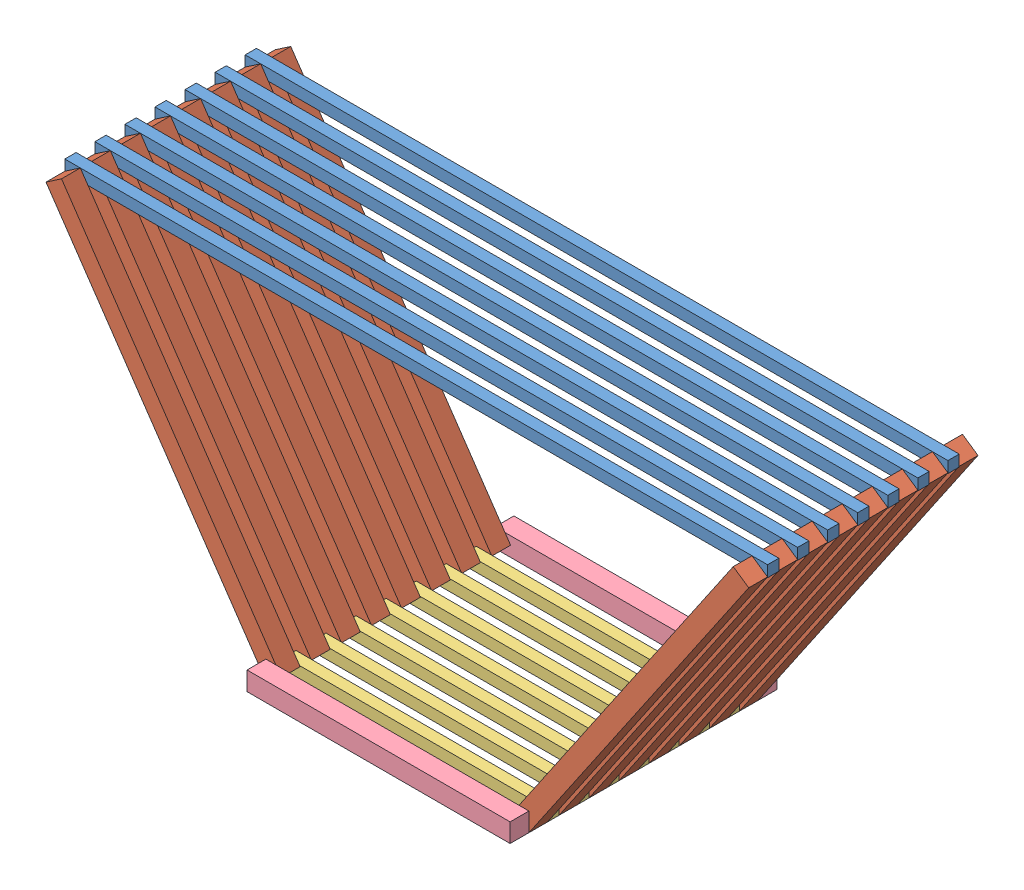
SolidWorks assembly section, configuration Default. Lengths in mm.
Overall size (187 88.5 71).
32 component instances, 4 part files, 107 mates.
Components (placement in the parent):
- bottom-1: bottom [Default] at (-2.2105 97.3296 181.7134) size (187 3 3)
- side-1: side [Default] at (-2.2105 97.5103 186.7134) x (0.563855 -0.825874 0) z (0 0 1) size (103.75 5 5)
- side-2: side [Default] at (126.2895 11.8259 186.7134) x (0.563855 0.825874 0) z (0 0 1) size (103.75 5 5)
- topmid-1: topmid [Default] at (56.2895 11.8259 189.7134) size (70 3 3)
- topmid-3: topmid [Default] at (56.2895 11.8259 181.7134) size (70 3 3)
- bottom-2: bottom [Default] at (-2.2105 97.3296 189.7134) size (187 3 3)
- side-3: side [Default] at (-2.2105 97.5103 138.7134) x (0.563855 -0.825874 0) z (0 0 1) size (103.75 5 5)
- side-4: side [Default] at (126.2895 11.8259 162.7134) x (0.563855 0.825874 0) z (0 0 1) size (103.75 5 5)
- side-5: side [Default] at (126.2895 11.8259 178.7134) x (0.563855 0.825874 0) z (0 0 1) size (103.75 5 5)
- side-6: side [Default] at (-2.2105 97.5103 178.7134) x (0.563855 -0.825874 0) z (0 0 1) size (103.75 5 5)
- side-7: side [Default] at (-2.2105 97.5103 194.7134) x (0.563855 -0.825874 0) z (0 0 1) size (103.75 5 5)
- side-8: side [Default] at (126.2895 11.8259 194.7134) x (0.563855 0.825874 0) z (0 0 1) size (103.75 5 5)
- side-9: side [Default] at (126.2895 11.8259 146.7134) x (0.563855 0.825874 0) z (0 0 1) size (103.75 5 5)
- side-10: side [Default] at (126.2895 11.8259 154.7134) x (0.563855 0.825874 0) z (0 0 1) size (103.75 5 5)
- side-11: side [Default] at (126.2895 11.8259 170.7134) x (0.563855 0.825874 0) z (0 0 1) size (103.75 5 5)
- side-12: side [Default] at (-2.2105 97.5103 162.7134) x (0.563855 -0.825874 0) z (0 0 1) size (103.75 5 5)
- side-13: side [Default] at (-2.2105 97.5103 170.7134) x (0.563855 -0.825874 0) z (0 0 1) size (103.75 5 5)
- side-14: side [Default] at (-2.2105 97.5103 154.7134) x (0.563855 -0.825874 0) z (0 0 1) size (103.75 5 5)
- side-15: side [Default] at (126.2895 11.8259 138.7134) x (0.563855 0.825874 0) z (0 0 1) size (103.75 5 5)
- side-16: side [Default] at (-2.2105 97.5103 146.7134) x (0.563855 -0.825874 0) z (0 0 1) size (103.75 5 5)
- topend-1: topend [Default] at (56.2895 11.8259 199.7134) size (70 5 5)
- topend-2: topend [Default] at (56.2895 11.8259 133.7134) size (70 5 5)
- topmid-4: topmid [Default] at (56.2895 11.8259 157.7134) size (70 3 3)
- topmid-5: topmid [Default] at (56.2895 11.8259 149.7134) size (70 3 3)
- topmid-6: topmid [Default] at (56.2895 11.8259 165.7134) size (70 3 3)
- topmid-7: topmid [Default] at (56.2895 11.8259 173.7134) size (70 3 3)
- topmid-8: topmid [Default] at (56.2895 11.8259 141.7134) size (70 3 3)
- bottom-3: bottom [Default] at (-2.2105 97.3296 173.7134) size (187 3 3)
- bottom-4: bottom [Default] at (-2.2105 97.3296 165.7134) size (187 3 3)
- bottom-5: bottom [Default] at (-2.2105 97.3296 157.7134) size (187 3 3)
- bottom-6: bottom [Default] at (-2.2105 97.3296 149.7134) size (187 3 3)
- bottom-7: bottom [Default] at (-2.2105 97.3296 141.7134) size (187 3 3)
Mates (geometry in assembly coordinates):
- Parallel34: parallel: line of side-7 through (-2.2105 97.5103 194.7134) axis (0.563855 -0.825874 0); line of side-1 through (-2.2105 97.5103 186.7134) axis (0.563855 -0.825874 0)
- Parallel35: parallel: line of topend-1 through (56.2895 11.8259 199.7134) axis (1 0 0); line of topmid-3 through (56.2895 11.8259 181.7134) axis (1 0 0)
- Parallel36: parallel: line of topend-1 through (56.2895 11.8259 199.7134) axis (1 0 0); line of topmid-7 through (56.2895 11.8259 173.7134) axis (1 0 0)
- Parallel37: parallel: line of topend-1 through (56.2895 11.8259 199.7134) axis (1 0 0); line of bottom-2 through (-2.2105 97.3296 189.7134) axis (1 0 0)
- Parallel38: parallel: line of topend-1 through (56.2895 11.8259 199.7134) axis (1 0 0); line of bottom-1 through (-2.2105 97.3296 181.7134) axis (1 0 0)
- Parallel40: parallel: line of side-1 through (-2.2105 97.5103 186.7134) axis (0.563855 -0.825874 0); line of side-6 through (-2.2105 97.5103 178.7134) axis (0.563855 -0.825874 0)
- Parallel41: parallel: line of side-2 through (126.2895 11.8259 186.7134) axis (0.563855 0.825874 0); line of side-8 through (126.2895 11.8259 194.7134) axis (0.563855 0.825874 0)
- Parallel42: parallel: line of side-2 through (126.2895 11.8259 186.7134) axis (0.563855 0.825874 0); line of side-5 through (126.2895 11.8259 178.7134) axis (0.563855 0.825874 0)
- Parallel43: parallel: line of topend-1 through (56.2895 11.8259 194.7134) axis (0 0 1); line of side-7 through (56.2895 11.8259 194.7134) axis (0 0 -1)
- Parallel44: parallel: line of topend-1 through (56.2895 11.8259 194.7134) axis (0 0 1); line of topmid-1 through (56.2895 11.8259 186.7134) axis (0 0 1)
- Parallel45: parallel: line of topend-1 through (56.2895 11.8259 194.7134) axis (0 0 1); line of side-1 through (56.2895 11.8259 186.7134) axis (0 0 -1)
- Parallel46: parallel: line of topend-1 through (56.2895 11.8259 194.7134) axis (0 0 1); line of topmid-3 through (56.2895 11.8259 178.7134) axis (0 0 1)
- Parallel47: parallel: line of topend-1 through (56.2895 11.8259 194.7134) axis (0 0 1); line of side-6 through (56.2895 11.8259 178.7134) axis (0 0 -1)
- Parallel48: parallel: line of topend-1 through (56.2895 11.8259 194.7134) axis (0 0 1); line of topmid-7 through (56.2895 11.8259 170.7134) axis (0 0 1)
- Parallel49: parallel: line of topend-1 through (56.2895 11.8259 194.7134) axis (0 0 1); line of topmid-7 through (126.2895 11.8259 173.7134) axis (0 0 -1)
- Parallel50: parallel: line of topend-1 through (56.2895 11.8259 194.7134) axis (0 0 1); line of side-5 through (126.2895 11.8259 173.7134) axis (0 0 1)
- Parallel51: parallel: line of topend-1 through (56.2895 11.8259 194.7134) axis (0 0 1); line of topmid-3 through (126.2895 11.8259 181.7134) axis (0 0 -1)
- Parallel52: parallel: line of topend-1 through (56.2895 11.8259 194.7134) axis (0 0 1); line of side-2 through (126.2895 11.8259 181.7134) axis (0 0 1)
- Parallel53: parallel: line of topend-1 through (56.2895 11.8259 194.7134) axis (0 0 1); line of topmid-1 through (126.2895 11.8259 189.7134) axis (0 0 -1)
- Parallel54: parallel: line of topend-1 through (56.2895 11.8259 194.7134) axis (0 0 1); line of side-8 through (126.2895 11.8259 189.7134) axis (0 0 1)
- Parallel55: parallel: line of topend-1 through (56.2895 11.8259 194.7134) axis (0 0 1); line of bottom-1 through (184.7895 97.3296 181.7134) axis (0 0 -1)
- Parallel56: parallel: line of topend-1 through (56.2895 11.8259 194.7134) axis (0 0 1); line of bottom-2 through (184.7895 97.3296 189.7134) axis (0 0 -1)
- Parallel57: parallel: line of topend-1 through (56.2895 11.8259 194.7134) axis (0 0 1); line of side-8 through (184.7895 97.5103 194.7134) axis (0 0 -1)
- Parallel58: parallel: line of topend-1 through (56.2895 11.8259 194.7134) axis (0 0 1); line of side-2 through (184.7895 97.5103 186.7134) axis (0 0 -1)
- Parallel59: parallel: line of topend-1 through (56.2895 11.8259 194.7134) axis (0 0 1); line of side-5 through (184.7895 97.5103 178.7134) axis (0 0 -1)
- Parallel60: parallel: line of topend-1 through (56.2895 11.8259 194.7134) axis (0 0 1); line of side-7 through (-2.2105 97.5103 189.7134) axis (0 0 1)
- Parallel61: parallel: line of topend-1 through (56.2895 11.8259 194.7134) axis (0 0 1); line of bottom-2 through (-2.2105 97.3296 186.7134) axis (0 0 1)
- Parallel62: parallel: line of topend-1 through (56.2895 11.8259 194.7134) axis (0 0 1); line of side-1 through (-2.2105 97.5103 181.7134) axis (0 0 1)
- Parallel63: parallel: line of topend-1 through (56.2895 11.8259 194.7134) axis (0 0 1); line of bottom-1 through (-2.2105 97.3296 178.7134) axis (0 0 1)
- Parallel64: parallel: line of topend-1 through (56.2895 11.8259 194.7134) axis (0 0 1); line of side-6 through (-2.2105 97.5103 173.7134) axis (0 0 1)
- Coincident68: coincident: point of side-7; point of topend-1
- Coincident69: coincident: point of topmid-1; point of side-7
- Coincident70: coincident: point of side-1; point of topmid-1
- Coincident71: coincident: point of side-1; point of topmid-3
- Coincident72: coincident: point of topmid-7; point of side-6
- Coincident73: coincident: point of topmid-3; point of side-6
- Coincident74: coincident: point of side-5; point of topmid-7
- Coincident75: coincident: point of side-2; point of topmid-3
- Coincident76: coincident: point of topmid-1; point of side-8
- Parallel65: parallel: line of topmid-1 through (56.2895 11.8259 189.7134) axis (1 0 0); line of topend-1 through (126.2895 11.8259 194.7134) axis (-1 0 0)
- Coincident85: coincident: point of side-1; line of bottom-2 through (184.7895 100.3296 186.7134) axis (-1 0 0)
- Coincident86: coincident: line of bottom-2 through (-2.2105 100.3296 189.7134) axis (1 0 0); point of side-8
- Coincident88: coincident: line of bottom-2 through (184.7895 100.3296 189.7134) axis (0 -1 0); point of side-8
- Coincident89: coincident: line of bottom-2 through (-2.2105 100.3296 189.7134) axis (0 -1 0); point of side-7
- Coincident90: coincident: line of bottom-1 through (-2.2105 100.3296 181.7134) axis (1 0 0); point of side-2
- Coincident91: coincident: line of bottom-1 through (184.7895 100.3296 181.7134) axis (0 -1 0); point of side-2
- Parallel67: parallel: line of bottom-1 through (184.7895 97.3296 178.7134) axis (-1 0 0); line of bottom-3 through (184.7895 97.3296 170.7134) axis (-1 0 0)
- Parallel68: parallel: line of bottom-1 through (184.7895 97.3296 181.7134) axis (0 0 -1); line of bottom-3 through (-2.2105 97.3296 170.7134) axis (0 0 1)
- Coincident95: coincident: point of side-5; line of bottom-3 through (-2.2105 100.3296 173.7134) axis (1 0 0)
- Coincident96: coincident: point of side-5; line of bottom-3 through (184.7895 100.3296 173.7134) axis (0 -1 0)
- Coincident99: coincident: point of side-13; point of topmid-7
- Parallel69: parallel: line of side-6 through (56.2895 11.8259 178.7134) axis (0 0 -1); line of side-13 through (56.2895 11.8259 170.7134) axis (0 0 -1)
- Parallel70: parallel: line of side-6 through (56.2895 11.8259 173.7134) axis (-0.563855 0.825874 0); line of side-13 through (-2.2105 97.5103 170.7134) axis (0.563855 -0.825874 0)
- Coincident102: coincident: point of side-11; point of topmid-7
- Parallel71: parallel: line of side-5 through (126.2895 11.8259 173.7134) axis (0 0 1); line of side-11 through (126.2895 11.8259 165.7134) axis (0 0 1)
- Parallel72: parallel: line of side-5 through (184.7895 97.5103 173.7134) axis (-0.563855 -0.825874 0); line of side-11 through (184.7895 97.5103 165.7134) axis (-0.563855 -0.825874 0)
- Coincident105: coincident: point of side-13; point of topmid-6
- Parallel73: parallel: line of topmid-6 through (56.2895 11.8259 162.7134) axis (0 0 1); line of topmid-7 through (56.2895 11.8259 170.7134) axis (0 0 1)
- Parallel74: parallel: line of topmid-6 through (56.2895 11.8259 165.7134) axis (1 0 0); line of topmid-7 through (126.2895 11.8259 170.7134) axis (-1 0 0)
- Coincident108: coincident: point of side-13; line of bottom-4 through (-2.2105 100.3296 165.7134) axis (0 -1 0)
- Coincident109: coincident: point of side-13; line of bottom-4 through (-2.2105 100.3296 165.7134) axis (1 0 0)
- Parallel75: parallel: line of bottom-3 through (184.7895 97.3296 170.7134) axis (-1 0 0); line of bottom-4 through (-2.2105 97.3296 165.7134) axis (1 0 0)
- Coincident111: coincident: point of side-4; point of topmid-6
- Parallel76: parallel: line of side-4 through (184.7895 97.5103 157.7134) axis (-0.563855 -0.825874 0); line of side-11 through (180.6601 100.3296 165.7134) axis (-0.563855 -0.825874 0)
- Parallel77: parallel: line of side-4 through (126.2895 11.8259 157.7134) axis (0 0 1); line of side-11 through (126.2895 11.8259 165.7134) axis (0 0 1)
- Coincident114: coincident: point of side-12; point of topmid-6
- Parallel78: parallel: line of side-12 through (60.4189 14.6452 157.7134) axis (-0.563855 0.825874 0); line of side-13 through (60.4189 14.6452 165.7134) axis (-0.563855 0.825874 0)
- Parallel79: parallel: line of side-12 through (56.2895 11.8259 162.7134) axis (0 0 -1); line of side-13 through (56.2895 11.8259 170.7134) axis (0 0 -1)
- Coincident117: coincident: point of side-4; point of topmid-4
- Parallel80: parallel: line of topmid-4 through (56.2895 11.8259 157.7134) axis (1 0 0); line of topmid-6 through (126.2895 11.8259 162.7134) axis (-1 0 0)
- Parallel81: parallel: line of side-12 through (56.2895 11.8259 162.7134) axis (0 0 -1); line of topmid-4 through (56.2895 11.8259 154.7134) axis (0 0 1)
- Coincident120: coincident: point of side-12; line of bottom-5 through (-2.2105 100.3296 157.7134) axis (0 -1 0)
- Coincident121: coincident: point of side-12; line of bottom-5 through (-2.2105 100.3296 157.7134) axis (1 0 0)
- Parallel82: parallel: line of bottom-4 through (184.7895 97.3296 162.7134) axis (-1 0 0); line of bottom-5 through (-2.2105 97.3296 157.7134) axis (1 0 0)
- Coincident123: coincident: point of side-14; point of topmid-4
- Parallel83: parallel: line of side-12 through (60.4189 14.6452 157.7134) axis (-0.563855 0.825874 0); line of side-14 through (56.2895 11.8259 149.7134) axis (-0.563855 0.825874 0)
- Coincident125: coincident: line of side-12 through (56.2895 11.8259 162.7134) axis (0 0 -1); line of side-14 through (56.2895 11.8259 154.7134) axis (0 0 -1)
- Coincident126: coincident: point of side-10; point of topmid-4
- Parallel84: parallel: line of side-4 through (180.6601 100.3296 157.7134) axis (-0.563855 -0.825874 0); line of side-10 through (180.6601 100.3296 149.7134) axis (-0.563855 -0.825874 0)
- Parallel85: parallel: line of side-4 through (126.2895 11.8259 157.7134) axis (0 0 1); line of side-10 through (126.2895 11.8259 149.7134) axis (0 0 1)
- Coincident129: coincident: point of side-14; point of topmid-5
- Parallel86: parallel: line of topmid-4 through (126.2895 11.8259 154.7134) axis (-1 0 0); line of topmid-5 through (56.2895 11.8259 149.7134) axis (1 0 0)
- Parallel87: parallel: line of side-14 through (56.2895 11.8259 154.7134) axis (0 0 -1); line of topmid-5 through (56.2895 11.8259 146.7134) axis (0 0 1)
- Coincident132: coincident: point of side-10; line of bottom-6 through (-2.2105 100.3296 149.7134) axis (1 0 0)
- Coincident133: coincident: point of side-10; line of bottom-6 through (184.7895 100.3296 149.7134) axis (0 -1 0)
- Parallel88: parallel: line of bottom-5 through (184.7895 97.3296 154.7134) axis (-1 0 0); line of bottom-6 through (-2.2105 97.3296 149.7134) axis (1 0 0)
- Coincident136: coincident: point of side-16; point of topmid-5
- Parallel90: parallel: line of side-14 through (60.4189 14.6452 149.7134) axis (-0.563855 0.825874 0); line of side-16 through (60.4189 14.6452 141.7134) axis (-0.563855 0.825874 0)
- Coincident138: coincident: line of side-14 through (56.2895 11.8259 154.7134) axis (0 0 -1); line of side-16 through (56.2895 11.8259 146.7134) axis (0 0 -1)
- Coincident139: coincident: point of side-9; point of topmid-5
- Parallel91: parallel: line of side-9 through (184.7895 97.5103 141.7134) axis (-0.563855 -0.825874 0); line of side-10 through (180.6601 100.3296 149.7134) axis (-0.563855 -0.825874 0)
- Parallel92: parallel: line of side-9 through (126.2895 11.8259 141.7134) axis (0 0 1); line of side-10 through (126.2895 11.8259 149.7134) axis (0 0 1)
- Coincident142: coincident: point of side-16; point of topmid-8
- Parallel93: parallel: line of topmid-5 through (126.2895 11.8259 146.7134) axis (-1 0 0); line of topmid-8 through (56.2895 11.8259 141.7134) axis (1 0 0)
- Parallel94: parallel: line of side-16 through (56.2895 11.8259 146.7134) axis (0 0 -1); line of topmid-8 through (56.2895 11.8259 138.7134) axis (0 0 1)
- Coincident145: coincident: point of side-3; point of topmid-8
- Parallel95: parallel: line of side-3 through (-2.2105 97.5103 138.7134) axis (0.563855 -0.825874 0); line of side-16 through (56.2895 11.8259 141.7134) axis (-0.563855 0.825874 0)
- Parallel96: parallel: line of side-3 through (56.2895 11.8259 138.7134) axis (0 0 -1); line of side-16 through (56.2895 11.8259 146.7134) axis (0 0 -1)
- Coincident148: coincident: point of side-15; point of topmid-8
- Parallel97: parallel: line of side-9 through (184.7895 97.5103 141.7134) axis (-0.563855 -0.825874 0); line of side-15 through (184.7895 97.5103 133.7134) axis (-0.563855 -0.825874 0)
- Parallel98: parallel: line of side-15 through (126.2895 11.8259 133.7134) axis (0 0 1); line of topmid-8 through (126.2895 11.8259 141.7134) axis (0 0 -1)
- Coincident151: coincident: point of side-3; point of topend-2
- Parallel99: parallel: line of topend-2 through (56.2895 11.8259 133.7134) axis (1 0 0); line of topmid-8 through (126.2895 11.8259 138.7134) axis (-1 0 0)
- Parallel100: parallel: line of side-3 through (56.2895 11.8259 138.7134) axis (0 0 -1); line of topend-2 through (56.2895 11.8259 128.7134) axis (0 0 1)
- Coincident158: coincident: point of side-3; line of bottom-7 through (184.7895 100.3296 138.7134) axis (-1 0 0)
- Coincident159: coincident: point of side-3; line of bottom-7 through (-2.2105 100.3296 138.7134) axis (0 -1 0)
- Parallel101: parallel: line of bottom-6 through (184.7895 97.3296 146.7134) axis (-1 0 0); line of bottom-7 through (-2.2105 97.3296 141.7134) axis (1 0 0)
